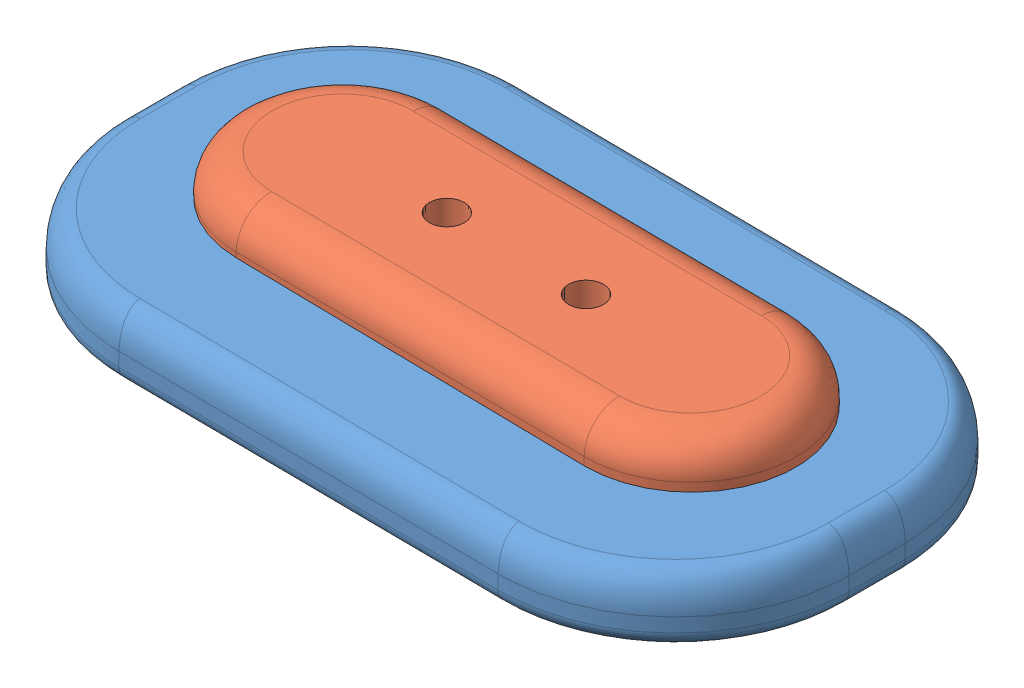
SolidWorks assembly left lock, configuration Default. Lengths in mm.
Overall size (104.13 16.4 58.05).
2 component instances, 2 part files, 0 mates.
Components (placement in the parent):
- Part2-1: Part2 [Default] at (35.6787 60.2189 80.9328) x (-0.999962 0.008727 0) z (0 0 1) size (104.05 10.05 58.05)
- Seguro bocina izquierda-1: Seguro bocina izquierda [Default] at (60.5964 56.1411 80.4914) x (0.008727 0 -0.999962) z (0.999962 0 0.008727) size (30 10.46 80)
